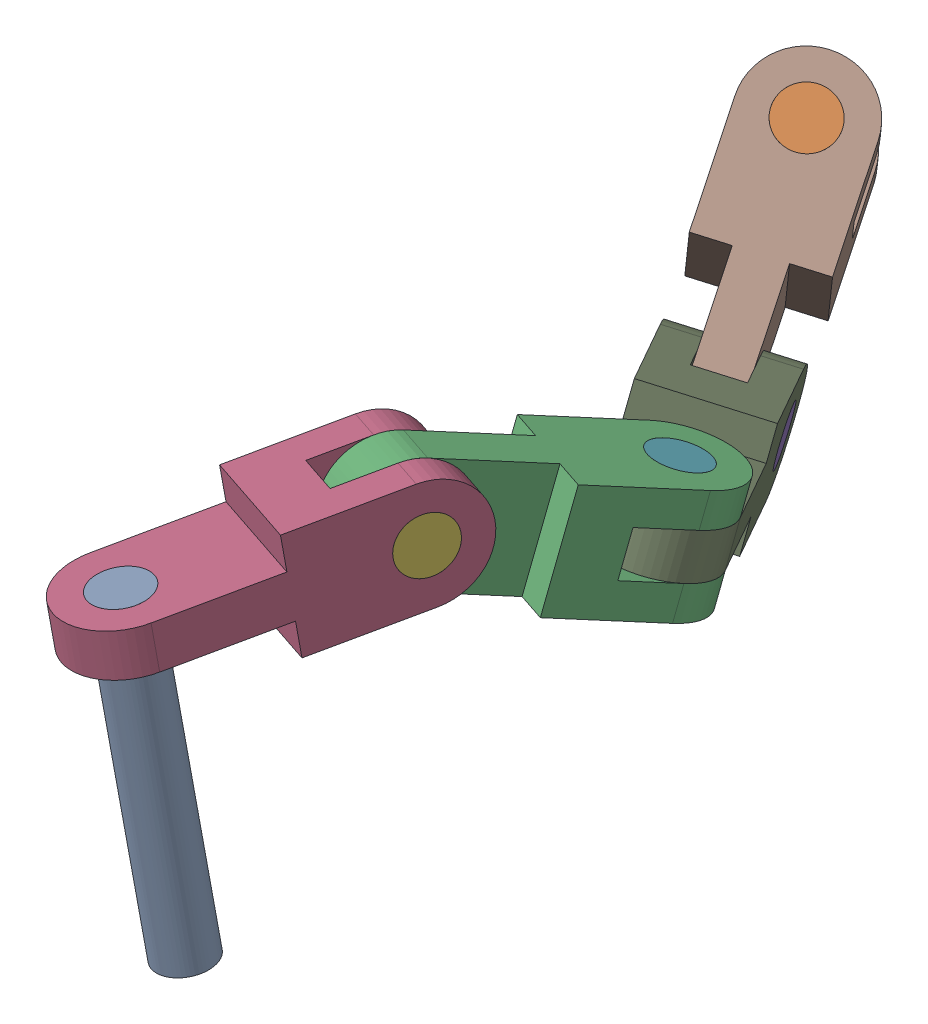
SolidWorks assembly cswa p1, configuration Default. Lengths in mm.
Overall size (385.03 393.27 869.05).
9 component instances, 3 part files, 20 mates.
Components (placement in the parent):
- long_pin-1: long_pin [Default] at (-17.8989 -3.5867 17.0811) x (0.992707 0.10689 0.055751) z (-0.045465 -0.09636 0.994308) size (50 300 50)
- long_pin-2: long_pin [Default] at (-26.0088 48.4455 -635.9808) x (0.884695 -0.45428 -0.104617) z (-0.104617 -0.412171 0.90508) size (50 300 50)
- chain_link-1: chain_link [Default] at (90.1875 -29.0117 -258.6247) x (0.930828 0.072152 0.358264) z (0.045872 0.949497 -0.310405) size (100 300 100)
- chain_link-2: chain_link [Default] at (19.1325 -10.9267 -77.6543) x (0.111654 -0.98959 -0.090797) z (0.930828 0.072152 0.358264) size (100 300 100)
- short_pin-1: short_pin [Default] at (57.0831 -116.8373 -532.1669) x (0.060585 0.955384 -0.289085) z (-0.553116 -0.208952 -0.806475) size (50 100 50)
- short_pin-2: short_pin [Default] at (7.3894 -2.0825 -188.487) x (-0.321774 -0.302966 0.897036) z (0.173265 -0.950266 -0.258792) size (50 100 50)
- short_pin-3: short_pin [Default] at (128.7378 -12.0736 -362.1958) x (0.930793 0.072181 0.358348) z (-0.362656 0.30536 0.880475) size (50 100 50)
- chain_link-6: chain_link [Default] at (-16.5923 -48.7214 -581.4837) x (0.830899 -0.208758 -0.515779) z (0.45428 0.789775 0.412171) size (100 300 100)
- chain_link-7: chain_link [Default] at (70.9912 -82.9739 -426.5268) x (-0.045872 -0.949497 0.310405) z (0.830899 -0.208758 -0.515779) size (100 300 100)
Mates (geometry in assembly coordinates):
- Concentric4: concentric anti-aligned: cylinder of long_pin-1 through (15.5972 -300.4639 -10.158) axis (-0.111654 0.98959 0.090797) radius 25; cylinder of chain_link-2 through (-21.2485 26.101 19.805) axis (0.111654 -0.98959 -0.090797) radius 25
- Coincident3: coincident aligned: plane of long_pin-1 through (-17.8989 -3.5867 17.0811) normal (-0.111654 0.98959 0.090797); plane of chain_link-2 through (-17.8989 -3.5867 17.0811) normal (-0.111654 0.98959 0.090797)
- Concentric5: concentric: cylinder of chain_link-2 through (7.3894 -2.0825 -188.487) axis (0.930828 0.072152 0.358264) radius 25; cylinder of short_pin-2 through (100.4722 5.1327 -152.6606) axis (-0.930828 -0.072152 -0.358264) radius 25
- Coincident4: coincident anti-aligned: circle of chain_link-2; circle of short_pin-2
- Concentric6: concentric: cylinder of chain_link-1 through (7.3894 -2.0825 -188.487) axis (0.930828 0.072152 0.358264) radius 25; cylinder of short_pin-2 through (100.4722 5.1327 -152.6606) axis (-0.930828 -0.072152 -0.358264) radius 25
- Angle2: planar angle = 0.436332 rad: plane of chain_link-1 through (128.7378 -12.0736 -362.1958) normal (0.045872 0.949497 -0.310405); plane of chain_link-2 through (60.0912 42.1604 -55.2013) normal (-0.111654 0.98959 0.090797)
- Coincident6: coincident anti-aligned: plane of chain_link-1 through (72.5474 2.9681 -163.4085) normal (0.930828 0.072152 0.358264); plane of chain_link-2 through (84.3639 58.6735 -205.3284) normal (-0.930828 -0.072152 -0.358264)
- Concentric7: concentric aligned: cylinder of chain_link-1 through (124.1506 -107.0233 -331.1554) axis (0.045872 0.949497 -0.310405) radius 25; cylinder of short_pin-3 through (124.1506 -107.0233 -331.1554) axis (0.045872 0.949497 -0.310405) radius 25
- Coincident7: coincident: circle of chain_link-1; circle of short_pin-3
- Concentric8: concentric: cylinder of short_pin-3 through (124.1506 -107.0233 -331.1554) axis (0.045872 0.949497 -0.310405) radius 25; cylinder of chain_link-7 through (128.7378 -12.0735 -362.1958) axis (-0.045872 -0.949497 0.310405) radius 25
- Coincident10: coincident anti-aligned: plane of chain_link-1 through (98.9486 -59.4345 -414.8223) normal (-0.045872 -0.949497 0.310405); plane of chain_link-7 through (127.3616 -40.5585 -352.8837) normal (0.045872 0.949497 -0.310405)
- Angle3: planar angle = 2.181662 rad anti-aligned: plane of chain_link-1 through (45.9397 14.8556 -292.0581) normal (-0.930828 -0.072152 -0.358264); plane of chain_link-7 through (-26.0067 -95.9615 -480.589) normal (-0.830899 0.208758 0.515779)
- Concentric9: concentric aligned: cylinder of short_pin-1 through (-26.0067 -95.9615 -480.589) axis (0.830899 -0.208758 -0.515779) radius 25; cylinder of chain_link-7 through (-26.0067 -95.9615 -480.589) axis (0.830899 -0.208758 -0.515779) radius 25
- Coincident12: coincident aligned: plane of short_pin-1 through (57.0831 -116.8373 -532.1669) normal (0.830899 -0.208758 -0.515779); plane of chain_link-7 through (57.0831 -116.8373 -532.1669) normal (0.830899 -0.208758 -0.515779)
- Concentric10: concentric aligned: cylinder of short_pin-1 through (-26.0067 -95.9615 -480.589) axis (0.830899 -0.208758 -0.515779) radius 25; cylinder of chain_link-6 through (-26.0067 -95.9615 -480.589) axis (0.830899 -0.208758 -0.515779) radius 25
- Coincident13: coincident: plane of chain_link-6 through (-1.0798 -102.2243 -496.0624) normal (-0.830899 0.208758 0.515779); plane of chain_link-7 through (-26.5127 -66.4622 -551.5082) normal (0.830899 -0.208758 -0.515779)
- Angle4: planar angle = 2.268928 rad anti-aligned: plane of chain_link-6 through (-26.0088 48.4455 -635.9808) normal (0.45428 0.789775 0.412171); plane of chain_link-7 through (114.8297 -45.9369 -467.8359) normal (0.045872 0.949497 -0.310405)
- Concentric11: concentric aligned: cylinder of long_pin-2 through (-162.2929 -188.487 -759.6322) axis (0.45428 0.789775 0.412171) radius 25; cylinder of chain_link-6 through (-71.4369 -30.532 -677.1979) axis (0.45428 0.789775 0.412171) radius 25
- Coincident15: coincident aligned: plane of long_pin-2 through (-26.0088 48.4455 -635.9808) normal (0.45428 0.789775 0.412171); plane of chain_link-6 through (-26.0088 48.4455 -635.9808) normal (0.45428 0.789775 0.412171)
- Coincident16: coincident: circle of chain_link-2
